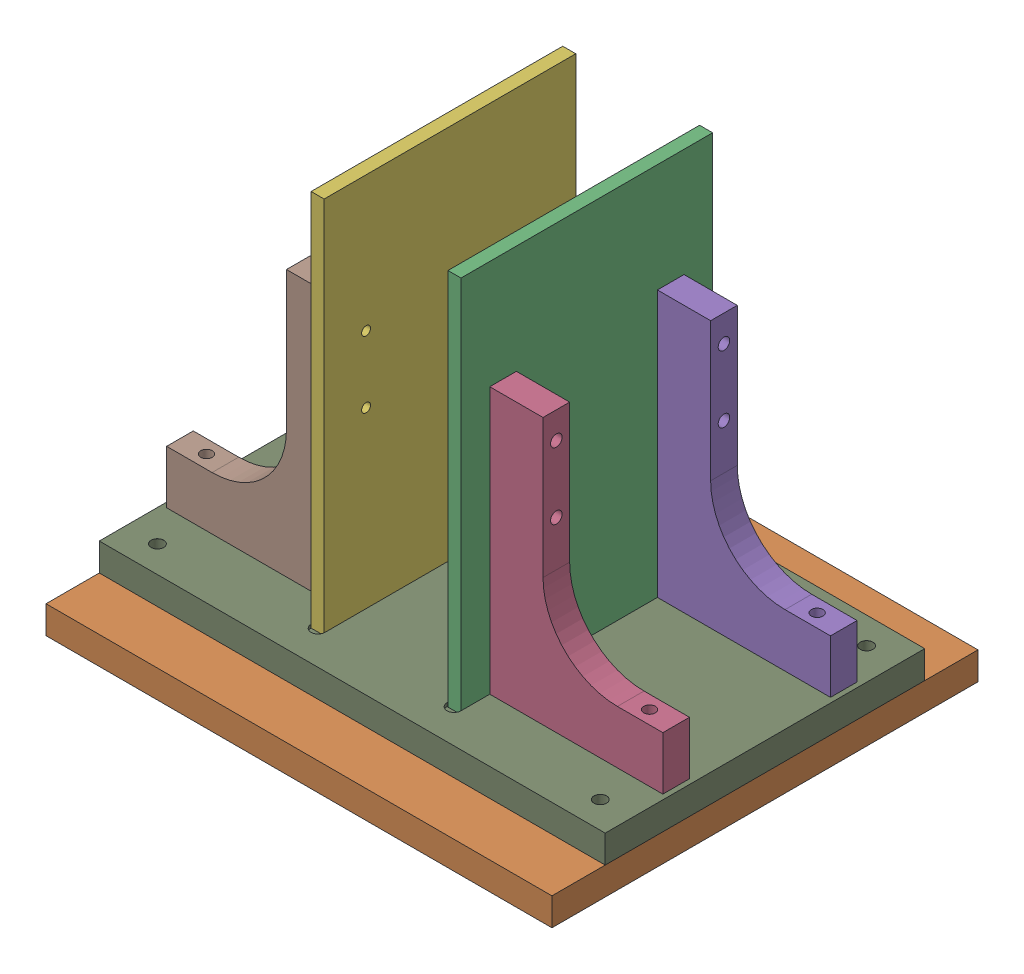
SolidWorks assembly Assem_module_test3, configuration Default. Lengths in mm.
Overall size (482.6 524.64 406.4).
9 component instances, 5 part files, 49 mates.
Components (placement in the parent):
- Module_base_9_tony-1: Module_base_9_tony [Default] at (0 -114.3 0) x (0.5 0 -0.866025) z (0.866025 0 0.5) size (152.4 114.3 152.4)
- bottom plate YL-1: bottom plate YL [Default] at origin size (482.6 26.42 406.4)
- Side Plate HS-1: Side Plate HS [Default] at (59.055 229.997 0.127) x (0 0 -1) z (0 -1 0) size (240.03 12.45 360.68)
- L-Bracket HS-1: L-Bracket HS [Default] at (71.501 112.1002 92.71) x (-1 0 0) z (0 0 -1) size (165.1 254 25.4)
- L-Bracket HS-2: L-Bracket HS [Default] at (71.501 112.1002 -67.183) x (-1 0 0) z (0 0 -1) size (165.1 254 25.4)
- Side Plate HS-2: Side Plate HS [Default] at (-71.501 229.997 0.127) x (0 0 -1) z (0 -1 0) size (240.03 12.45 360.68)
- L-Bracket HS-3: L-Bracket HS [Default] at (-71.501 112.1002 -92.583) size (165.1 254 25.4)
- L-Bracket HS-4: L-Bracket HS [Default] at (-71.501 112.1002 67.437) size (165.1 254 25.4)
- top plate YL (2024-02-22 JW)-2: top plate YL (2024-02-22 JW) [Default] at (0 26.416 0) size (482.6 26.42 304.8)
Mates (geometry in assembly coordinates):
- Concentric1: concentric aligned: cylinder of Module_base_9_tony-1 through (-27.85 0 48.2376) axis (0 1 0) radius 5.25; cylinder of bottom plate YL-1 through (-27.85 26.416 48.2376) axis (0 1 0) radius 5.5
- Concentric2: concentric aligned: cylinder of Module_base_9_tony-1 through (27.85 0 -48.2376) axis (0 1 0) radius 5.25; cylinder of bottom plate YL-1 through (27.85 26.416 -48.2376) axis (0 1 0) radius 5.5
- Concentric3: concentric aligned: cylinder of bottom plate YL-1 through (28.0762 46.1439 207.6861) axis (0 1 0) radius 1.27; cylinder of top plate YL-1 through (41.9544 72.5599 182.9558) axis (0 1 0) radius 6
- Parallel1: parallel aligned: cylinder of bottom plate YL-1 through (-20.6057 46.1439 -196.6734) axis (0 1 0) radius 1.27; cylinder of top plate YL-1 through (-332.7762 72.5599 22.9558) axis (0 1 0) radius 6
- Concentric6: concentric aligned: cylinder of bottom plate YL-1 through (28.0762 46.1439 207.6861) axis (0 1 0) radius 1.27; cylinder of top plate YL-2 through (28.0762 72.5599 207.6861) axis (0 1 0) radius 6
- Concentric7: concentric aligned: cylinder of bottom plate YL-1 through (15.3436 46.1439 185.6325) axis (0 1 0) radius 1.27; cylinder of top plate YL-2 through (15.3436 72.5599 185.6325) axis (0 1 0) radius 6
- Coincident3: coincident anti-aligned: plane of bottom plate YL-1 through (0 26.416 0) normal (0 1 0); plane of top plate YL-2 through (3.6756 72.5599 5.423) normal (0 -1 0)
- Coincident5: coincident anti-aligned: plane of top plate YL-2 through (3.6756 95.8009 5.423) normal (0 1 0); plane of Side Plate HS-1 through (71.501 49.657 120.142) normal (0 -1 0)
- Coincident6: coincident anti-aligned: plane of top plate YL-2 through (33.6756 95.8009 57.3846) normal (0.5 0 0.866025); plane of Side Plate HS-1 through (59.055 229.997 0.127) normal (-1 0 0)
- Coincident12: coincident anti-aligned: line of top plate YL-2 through (-70.3704 95.8009 117.4556) axis (0 1 0); line of Side Plate HS-1 through (59.055 410.337 120.142) axis (0 -1 0)
- Coincident13: coincident anti-aligned: plane of top plate YL-2 through (3.6756 98.9759 5.423) normal (0 1 0); plane of L-Bracket HS-1 through (71.501 52.832 67.31) normal (0 -1 0)
- Coincident15: coincident anti-aligned: plane of Module_base_9_tony-1 through (0 0 0) normal (0 1 0); plane of bottom plate YL-1 through (0 0 0) normal (0 -1 0)
- Parallel8: parallel aligned: cylinder of Side Plate HS-1 through (71.501 281.432 80.137) axis (1 0 0) radius 4.25; cylinder of L-Bracket HS-1 through (122.301 281.432 80.01) axis (1 0 0) radius 5.5
- Concentric12: concentric aligned: cylinder of top plate YL-2 through (15.3436 72.5599 185.6325) axis (0 1 0) radius 6; cylinder of L-Bracket HS-1 through (14.2548 149.7759 183.7467) axis (0 1 0) radius 6
- Concentric13: concentric aligned: cylinder of Side Plate HS-1 through (71.501 281.432 -79.883) axis (1 0 0) radius 4.25; cylinder of L-Bracket HS-2 through (122.301 281.432 -79.883) axis (1 0 0) radius 5.5
- Parallel9: parallel aligned: cylinder of top plate YL-2 through (166.6403 72.5599 127.6861) axis (0 1 0) radius 6; cylinder of L-Bracket HS-2 through (211.201 103.632 -79.883) axis (0 1 0) radius 5.5
- Coincident16: coincident anti-aligned: plane of Side Plate HS-1 through (71.501 229.997 0.127) normal (1 0 0); plane of L-Bracket HS-2 through (71.501 306.832 -92.583) normal (-1 0 0)
- Coincident17: coincident anti-aligned: plane of top plate YL-2 through (3.6756 95.8009 5.423) normal (0 1 0); plane of Side Plate HS-2 through (-59.055 49.657 120.142) normal (0 -1 0)
- Coincident20: coincident aligned: line of top plate YL-2 through (-130.3704 95.8009 13.5325) axis (0.866025 0 -0.5); line of Side Plate HS-2 through (-59.055 49.657 120.142) axis (0 0 -1)
- Coincident21: coincident: point of top plate YL-2; unknown of Side Plate HS-2
- Concentric15: concentric anti-aligned: cylinder of Side Plate HS-2 through (-59.055 281.432 -79.883) axis (1 0 0) radius 4.25; cylinder of L-Bracket HS-3 through (-122.301 281.432 -79.883) axis (-1 0 0) radius 5.5
- Coincident22: coincident anti-aligned: plane of Side Plate HS-2 through (-71.501 229.997 0.127) normal (-1 0 0); plane of L-Bracket HS-3 through (-71.501 306.832 -67.183) normal (1 0 0)
- Concentric16: concentric anti-aligned: cylinder of Side Plate HS-2 through (-59.055 281.432 80.137) axis (1 0 0) radius 4.25; cylinder of L-Bracket HS-4 through (-122.301 281.432 80.137) axis (-1 0 0) radius 5.5
- Coincident23: coincident anti-aligned: plane of Side Plate HS-2 through (-71.501 229.997 0.127) normal (-1 0 0); plane of L-Bracket HS-4 through (-71.501 306.832 92.837) normal (1 0 0)
- Coincident24: coincident: plane of bottom plate YL-1 through (0 26.416 0) normal (0 1 0); plane of top plate YL (2024-02-22 JW)-1 through (14.3192 72.5599 -181.3549) normal (0 -1 0)
- Concentric17: concentric: cylinder of bottom plate YL-1 through (-158.1317 72.5599 -114.8355) axis (0 1 0) radius 5.25; cylinder of top plate YL (2024-02-22 JW)-1 through (-170.8308 72.5599 -92.8368) axis (0 1 0) radius 6.35
- Concentric22: concentric: cylinder of bottom plate YL-1 through (-145.3991 72.5599 -92.7819) axis (0 1 0) radius 5.25; cylinder of top plate YL (2024-02-22 JW)-1 through (-145.4308 72.5599 -92.8368) axis (0 1 0) radius 6.35
- Coincident28: coincident aligned: line of Side Plate HS-2 through (-71.501 49.657 120.142) axis (0 0 -1); line of top plate YL (2024-02-22 JW)-2 through (-71.501 49.657 120.142) axis (0 0 -1)
- Coincident29: coincident: unknown of Side Plate HS-2; unknown of top plate YL (2024-02-22 JW)-2
- Coincident30: coincident anti-aligned: plane of Side Plate HS-1 through (71.501 229.997 0.127) normal (1 0 0); plane of top plate YL (2024-02-22 JW)-2 through (71.501 49.657 0) normal (-1 0 0)
- Coincident31: coincident anti-aligned: line of Side Plate HS-1 through (71.501 410.337 120.142) axis (0 -1 0); line of top plate YL (2024-02-22 JW)-2 through (71.501 49.657 120.142) axis (0 1 0)
- Coincident32: coincident anti-aligned: plane of Side Plate HS-1 through (71.501 229.997 0.127) normal (1 0 0); plane of L-Bracket HS-1 through (71.501 306.832 67.31) normal (-1 0 0)
- Coincident33: coincident anti-aligned: plane of Side Plate HS-1 through (71.501 229.997 0.127) normal (1 0 0); plane of L-Bracket HS-2 through (71.501 306.832 -92.583) normal (-1 0 0)
- Coincident34: coincident anti-aligned: plane of Side Plate HS-1 through (71.501 49.657 120.142) normal (0 -1 0); plane of top plate YL (2024-02-22 JW)-2 through (0 49.657 0) normal (0 1 0)
- Coincident35: coincident anti-aligned: plane of L-Bracket HS-3 through (-71.501 52.832 -67.183) normal (0 -1 0); plane of top plate YL (2024-02-22 JW)-2 through (0 52.832 0) normal (0 1 0)
- Coincident37: coincident anti-aligned: plane of L-Bracket HS-4 through (-71.501 52.832 92.837) normal (0 -1 0); plane of top plate YL (2024-02-22 JW)-2 through (0 52.832 0) normal (0 1 0)
- Coincident38: coincident anti-aligned: plane of L-Bracket HS-1 through (71.501 52.832 67.31) normal (0 -1 0); plane of top plate YL (2024-02-22 JW)-2 through (0 52.832 0) normal (0 1 0)
- Concentric24: concentric aligned: cylinder of L-Bracket HS-1 through (211.201 103.632 80.01) axis (0 1 0) radius 5.5; cylinder of top plate YL (2024-02-22 JW)-2 through (211.201 26.416 80.01) axis (0 1 0) radius 6.35
- Coincident39: coincident anti-aligned: plane of L-Bracket HS-2 through (71.501 52.832 -92.583) normal (0 -1 0); plane of top plate YL (2024-02-22 JW)-2 through (0 52.832 0) normal (0 1 0)
- Coincident41: coincident anti-aligned: plane of Side Plate HS-2 through (-71.501 229.997 0.127) normal (-1 0 0); plane of top plate YL (2024-02-22 JW)-2 through (-71.501 49.657 0) normal (1 0 0)
- Coincident42: coincident anti-aligned: plane of Side Plate HS-1 through (71.501 229.997 0.127) normal (1 0 0); plane of top plate YL (2024-02-22 JW)-2 through (71.501 49.657 0) normal (-1 0 0)
- Concentric25: concentric aligned: cylinder of Module_base_9_tony-1 through (27.85 0 48.2376) axis (0 1 0) radius 5.25; cylinder of bottom plate YL-1 through (27.85 26.416 48.2376) axis (0 1 0) radius 5.5
- Concentric26: concentric aligned: cylinder of Module_base_9_tony-1 through (-27.85 0 -48.2376) axis (0 1 0) radius 5.25; cylinder of bottom plate YL-1 through (-27.85 26.416 -48.2376) axis (0 1 0) radius 5.5
- Coincident44: coincident aligned: line of bottom plate YL-1 through (241.3 26.416 203.2) axis (0 0 -1); line of top plate YL (2024-02-22 JW)-2 through (241.3 26.416 152.4) axis (0 0 -1)
- Coincident45: coincident anti-aligned: plane of bottom plate YL-1 through (0 26.416 0) normal (0 1 0); plane of top plate YL (2024-02-22 JW)-2 through (0 26.416 0) normal (0 -1 0)
- Width1: width anti-aligned: plane of top plate YL (2024-02-22 JW)-2 through (-241.3 52.832 152.4) normal (0 0 1); plane of bottom plate YL-1 through (-241.3 52.832 -152.4) normal (0 0 -1); plane of top plate YL (2024-02-22 JW)-2 through (-241.3 26.416 -203.2) normal (0 0 -1); plane of bottom plate YL-1 through (-241.3 26.416 203.2) normal (0 0 1)
- Concentric27: concentric aligned: cylinder of Module_base_9_tony-1 through (55.7 0 0) axis (0 1 0) radius 5.25; cylinder of bottom plate YL-1 through (55.7 26.416 0) axis (0 1 0) radius 5.5
- Concentric28: concentric aligned: cylinder of Module_base_9_tony-1 through (27.85 0 48.2376) axis (0 1 0) radius 5.25; cylinder of bottom plate YL-1 through (27.85 26.416 48.2376) axis (0 1 0) radius 5.5
- Coincident48: coordinate: unknown of bottom plate YL-1
